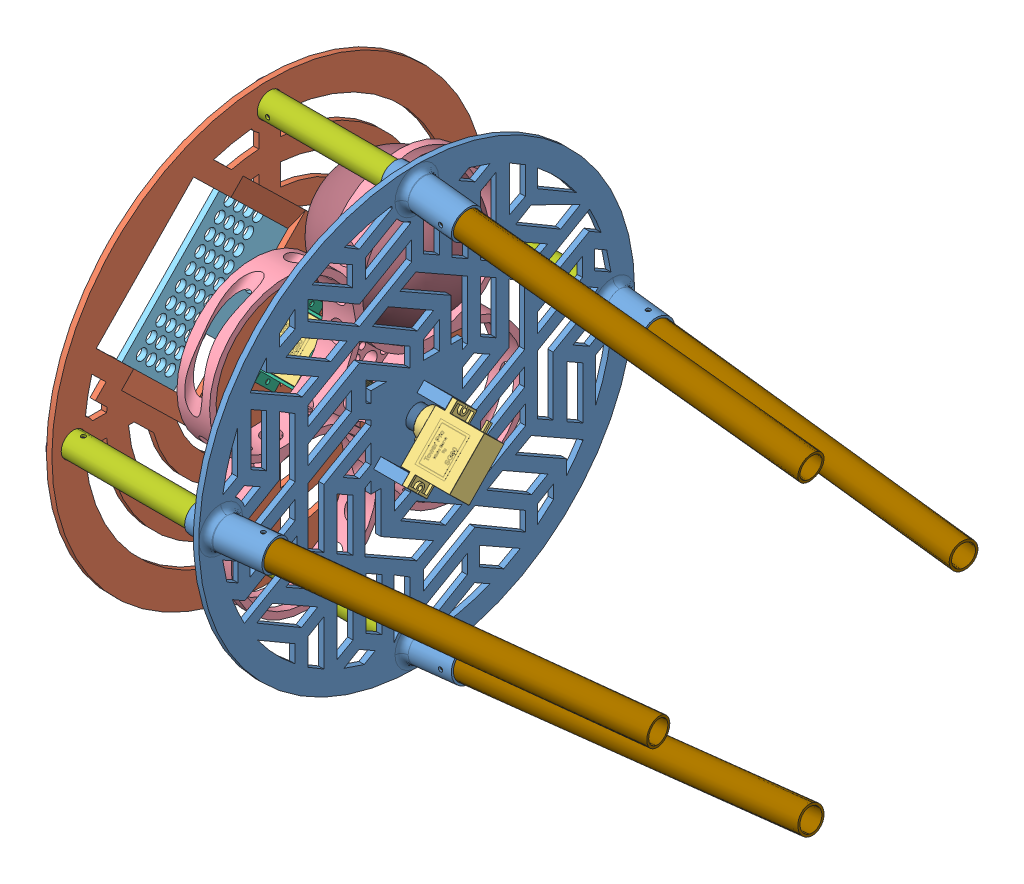
SolidWorks assembly Yük Bırakma Mekanizması Vol.4, configuration Varsayılan. Lengths in mm.
Overall size (264.31 282.82 282.82).
33 component instances, 22 part files, 41 mates.
Components (placement in the parent):
- Üst Tabla-1: Üst Tabla [Varsayılan] at (22.8768 -212.3675 0.7658) x (0 1 0) z (0 0 1) size (200 33.66 200)
- Alt Tabla-1: Alt Tabla [Varsayılan] at (-47.1232 -212.3675 0.7658) x (0 -0.716174 0.697921) z (0 0.697921 0.716174) size (200 15.35 200)
- TP SG90-1: TP SG90 [Varsayılan] at (-20.5232 -212.3747 0.7727) x (0 -0.697921 -0.716174) z (0 0.716174 -0.697921) size (12.64 29.82 33.01)
- Yük Tutucu-1: Yük Tutucu [Varsayılan] at (1.2768 -212.3675 0.7658) x (0 -0.596582 -0.802552) z (0 0.802552 -0.596582) size (166 20 166)
- TP SG90-2: TP SG90 [Varsayılan] at (54.1268 -216.1275 4.4299) x (0 -0.697921 -0.716174) z (0 0.716174 -0.697921) size (12.64 29.82 33.01)
- Alt Kapak-1: Alt Kapak [Varsayılan] at (-49.6232 -142.9176 16.8643) x (0 -0.716174 0.697921) z (0 0.697921 0.716174) size (73 2.5 85)
- Denge Parçası-1: Denge Parçası [Varsayılan] at (-36.3732 -208.3933 -11.8341) x (0 -0.716174 0.697921) z (0 0.697921 0.716174) size (33.3 22.15 19.25)
- karbonfiber boru 11x70-5: karbonfiber boru 11x70 [Varsayılan] at (-47.1232 -302.3675 0.7658) x (0 1 0) z (1 0 0) size (11 11 67.5)
- Bağlantı Parçası-1: Bağlantı Parçası [Varsayılan] at (-49.1232 -302.3675 0.7658) x (0 1 0) z (0 0 -1) size (16.34 15 16.34)
- karbonfiber boru 11x70-12: karbonfiber boru 11x70 [Varsayılan] at (-47.1232 -212.3675 90.7658) x (0 0 -1) z (1 0 0) size (11 11 67.5)
- karbonfiber boru 11x70-13: karbonfiber boru 11x70 [Varsayılan] at (-47.1232 -122.3675 0.7658) x (0 -1 0) z (1 0 0) size (11 11 67.5)
- karbonfiber boru 11x70-14: karbonfiber boru 11x70 [Varsayılan] at (-47.1232 -212.3675 -89.2342) x (0 0 1) z (1 0 0) size (11 11 67.5)
- Bağlantı Parçası-5: Bağlantı Parçası [Varsayılan] at (-49.1232 -212.3675 90.7658) x (0 0 -1) z (0 -1 0) size (16.34 15 16.34)
- Bağlantı Parçası-6: Bağlantı Parçası [Varsayılan] at (-49.1232 -122.3675 0.7658) x (0 -1 0) z (0 0 1) size (16.34 15 16.34)
- Bağlantı Parçası-7: Bağlantı Parçası [Varsayılan] at (-49.1232 -212.3675 -89.2342) x (0 0 1) z (0 1 0) size (16.34 15 16.34)
- karbonfiber boru 12x169-2: karbonfiber boru 12x169 [Varsayılan] at (35.8145 -212.3675 89.6511) x (0 1 0) z (0.993768 0 -0.111469) size (12 12 169)
- karbonfiber boru 12x169-9: karbonfiber boru 12x169 [Varsayılan] at (35.8145 -301.2529 0.7658) x (0 0 1) z (0.993768 0.111469 0) size (12 12 169)
- karbonfiber boru 12x169-10: karbonfiber boru 12x169 [Varsayılan] at (35.8145 -212.3675 -88.1195) x (0 -1 0) z (0.993768 0 0.111469) size (12 12 169)
- karbonfiber boru 12x169-11: karbonfiber boru 12x169 [Varsayılan] at (35.8145 -123.4822 0.7658) x (0 0 -1) z (0.993768 -0.111469 0) size (12 12 169)
- Aktarma Parçası-2: Aktarma Parçası [Varsayılan] at (27.3268 -212.3675 0.7658) x (0 0.18119 0.983448) z (0 -0.983448 0.18119) size (9.65 15 9.65)
- alt kapak bağlantısı-1: alt kapak bağlantısı [Varsayılan] at (-46.6232 -208.6148 -2.8913) x (0 -0.717149 0.69692) z (0 -0.69692 -0.717149) size (5.8 3 10.81)
- Yivli mil-1: Yivli mil [Varsayılan] at (-11.7232 -212.3675 0.7658) x (0 0.999999 0.001718) z (0 0.001718 -0.999999) size (5.06 32.34 5.78)
- Top-1: Top [Varsayılan] at (-14.6232 -173.845 -27.8701) x (-0.869488 -0.236482 -0.433667) z (-0.460523 0.070599 0.884836) size (60 60 60)
- inafag_625-2z_6leky27aadc6c6egwocnas8n-1: inafag_625-2z_6leky27aadc6c6egwocnas8n [Default] at (-14.2232 -212.3675 0.7658) x (-1 0 0) z (0 -0.938946 -0.344066) size (5.01 16 16)
  - inafag_625-2z_6leky27aadc6c6egwocnas8n_01-1: inafag_625-2z_6leky27aadc6c6egwocnas8n_01 [Default] at origin size (5 16 16)
  - inafag_625-2z_6leky27aadc6c6egwocnas8n_02-1: inafag_625-2z_6leky27aadc6c6egwocnas8n_02 [Default] at origin size (5.01 8.5 8.5)
  - inafag_625-2z_6leky27aadc6c6egwocnas8n_03-1: inafag_625-2z_6leky27aadc6c6egwocnas8n_03 [Default] at origin size (3.8 11.99 11.99)
  - inafag_625-2z_6leky27aadc6c6egwocnas8n_04-1: inafag_625-2z_6leky27aadc6c6egwocnas8n_04 [Default] at origin size (4.05 4.13 4.2)
  - inafag_625-2z_6leky27aadc6c6egwocnas8n_05-1: inafag_625-2z_6leky27aadc6c6egwocnas8n_05 [Default] at origin size (3.85 4.1 3.78)
  - inafag_625-2z_6leky27aadc6c6egwocnas8n_06-1: inafag_625-2z_6leky27aadc6c6egwocnas8n_06 [Default] at origin size (3.6 4.12 3.67)
  - inafag_625-2z_6leky27aadc6c6egwocnas8n_07-1: inafag_625-2z_6leky27aadc6c6egwocnas8n_07 [Default] at origin size (4.06 4.14 4.12)
  - inafag_625-2z_6leky27aadc6c6egwocnas8n_08-1: inafag_625-2z_6leky27aadc6c6egwocnas8n_08 [Default] at origin size (0.3 13.2 13.2)
  - inafag_625-2z_6leky27aadc6c6egwocnas8n_09-1: inafag_625-2z_6leky27aadc6c6egwocnas8n_09 [Default] at origin size (0.3 13.2 13.2)
Mates (geometry in assembly coordinates):
- Eş Merkezli1: concentric anti-aligned: cylinder of Üst Tabla-1 through (20.3768 -212.3675 0.7658) axis (1 0 0) radius 100; cylinder of Alt Tabla-1 through (-44.6232 -212.3675 0.7658) axis (-1 0 0) radius 100
- Eş Merkezli2: concentric aligned: cylinder of TP SG90-1 through (-43.0232 -213.0909 1.4707) axis (-1 0 0) radius 1.375; cylinder of Alt Tabla-1 through (-44.6232 -213.0909 1.4707) axis (-1 0 0) radius 1.775
- Çakışık3: coincident aligned: plane of Alt Tabla-1 through (-47.1232 -212.3675 0.7658) normal (-1 0 0); plane of TP SG90-1 through (-47.1232 -209.1072 -2.4115) normal (-1 0 0)
- Paralel1: parallel aligned: plane of Alt Tabla-1 through (-44.6232 -178.2832 -10.1089) normal (0 0.697921 0.716174); plane of TP SG90-1 through (-31.7732 -208.0127 5.2488) normal (0 0.697921 0.716174)
- Paralel2: parallel aligned: plane of Alt Tabla-1 through (-44.6232 -178.2832 -10.1089) normal (0 0.697921 0.716174); plane of TP SG90-2 through (42.8768 -211.7654 8.9059) normal (0 0.697921 0.716174)
- Çakışık8: coincident anti-aligned: plane of Alt Tabla-1 through (-47.1232 -212.3675 0.7658) normal (-1 0 0); plane of Alt Kapak-1 through (-47.1232 -142.9176 16.8643) normal (1 0 0)
- Eş Merkezli10: concentric aligned: cylinder of Alt Tabla-1 through (-44.6232 -208.6148 -2.8913) axis (-1 0 0) radius 6.65; cylinder of Alt Kapak-1 through (-47.1232 -208.6148 -2.8913) axis (-1 0 0) radius 3
- Açıyı Sınırla2: limit planar angle = 0 rad anti-aligned: plane of Alt Kapak-1 through (-47.1232 -195.1983 67.8126) normal (0 -0.716174 0.697921); plane of Alt Tabla-1 through (-51.1232 -237.4336 25.193) normal (0 0.716174 -0.697921)
- Uzaklık1: distance = 0.15 mm anti-aligned: plane of TP SG90-1 through (-36.3732 -204.1387 -7.2533) normal (0 0.716174 -0.697921); plane of Denge Parçası-1 through (-36.3732 -199.6693 -2.8819) normal (0 -0.716174 0.697921)
- Çakışık10: coincident anti-aligned: plane of TP SG90-1 through (-36.3732 -200.5578 -10.743) normal (1 0 0); plane of Denge Parçası-1 through (-36.3732 -199.6693 -2.8819) normal (-1 0 0)
- Çakışık12: coincident aligned: plane of TP SG90-1 through (-31.7732 -208.0127 5.2488) normal (0 0.697921 0.716174); plane of Denge Parçası-1 through (-36.3732 -199.6693 -2.8819) normal (0 0.697921 0.716174)
- Çakışık19: coincident aligned: plane of Alt Tabla-1 through (-47.1232 -212.3675 0.7658) normal (-1 0 0); plane of karbonfiber boru 11x70-5 through (-47.1232 -302.3675 0.7658) normal (-1 0 0)
- Çakışık20: coincident anti-aligned: plane of Üst Tabla-1 through (20.3768 -212.3675 0.7658) normal (-1 0 0); plane of karbonfiber boru 11x70-5 through (20.3768 -302.3675 0.7658) normal (1 0 0)
- Eş Merkezli15: concentric aligned: cylinder of Alt Tabla-1 through (-38.7732 -302.3675 0.7658) axis (-1 0 0) radius 5.7; cylinder of karbonfiber boru 11x70-5 through (20.3768 -302.3675 0.7658) axis (-1 0 0) radius 5.5
- Eş Merkezli17: concentric anti-aligned: cylinder of Üst Tabla-1 through (12.8768 -302.3675 0.7658) axis (1 0 0) radius 5.55; cylinder of karbonfiber boru 11x70-5 through (20.3768 -302.3675 0.7658) axis (-1 0 0) radius 5.5
- Eş Merkezli19: concentric anti-aligned: cylinder of Üst Tabla-1 through (20.3768 -212.3675 0.7658) axis (1 0 0) radius 100; cylinder of Yük Tutucu-1 through (-18.7232 -212.3675 0.7658) axis (-1 0 0) radius 2.4
- Eş Merkezli21: concentric anti-aligned: cylinder of Üst Tabla-1 through (20.3768 -212.3675 0.7658) axis (1 0 0) radius 100; cylinder of TP SG90-2 through (31.6268 -212.3675 0.7658) axis (-1 0 0) radius 6.25
- Paralel10: parallel aligned: plane of Üst Tabla-1 through (35.8768 -208.6708 -11.7033) normal (0 -0.697921 -0.716174); plane of TP SG90-2 through (42.8768 -220.4895 -0.0462) normal (0 -0.697921 -0.716174)
- Paralel11: parallel aligned: plane of Üst Tabla-1 through (35.8768 -199.8072 -2.6079) normal (0 0.716174 -0.697921); plane of TP SG90-2 through (35.8768 -204.3106 -7.0858) normal (0 0.716174 -0.697921)
- Eş Merkezli22: concentric aligned: cylinder of karbonfiber boru 11x70-5 through (20.3768 -302.3675 0.7658) axis (-1 0 0) radius 4.5; cylinder of Bağlantı Parçası-1 through (-34.1232 -302.3675 0.7658) axis (-1 0 0) radius 4.4
- Çakışık30: coincident anti-aligned: plane of Alt Tabla-1 through (-47.1232 -212.3675 0.7658) normal (-1 0 0); plane of Bağlantı Parçası-1 through (-47.1232 -302.3675 0.7658) normal (1 0 0)
- Eş Merkezli23: concentric anti-aligned: cylinder of karbonfiber boru 11x70-5 through (-40.1232 -302.3675 -4.7342) axis (0 0 1) radius 1; cylinder of Bağlantı Parçası-1 through (-40.1232 -302.3675 8.9371) axis (0 0 -1) radius 1
- Eş Merkezli24: concentric anti-aligned: cylinder of Üst Tabla-1 through (35.8145 -212.3675 89.6511) axis (0.993768 0 -0.111469) radius 6.05; cylinder of karbonfiber boru 12x169-2 through (203.7612 -212.3675 70.8128) axis (-0.993768 0 0.111469) radius 6
- Çakışık31: coincident anti-aligned: plane of Üst Tabla-1 through (35.8145 -212.3675 89.6511) normal (0.993768 0 -0.111469); plane of karbonfiber boru 12x169-2 through (35.8145 -212.3675 89.6511) normal (-0.993768 0 0.111469)
- Eş Merkezli27: concentric aligned: cylinder of Üst Tabla-1 through (15.3768 -122.3675 100.7658) axis (0 0 -1) radius 1; cylinder of karbonfiber boru 11x70-13 through (15.3768 -122.3675 6.2658) axis (0 0 -1) radius 1
- Eş Merkezli28: concentric aligned: cylinder of Üst Tabla-1 through (40.7833 -312.3675 89.0937) axis (0 1 0) radius 1; cylinder of karbonfiber boru 12x169-2 through (40.7833 -218.3675 89.0937) axis (0 1 0) radius 1
- Coincident4: coincident anti-aligned: plane of Üst Tabla-1 through (35.8768 -212.3675 0.7658) normal (1 0 0); plane of TP SG90-2 through (35.8768 -207.8915 -3.5962) normal (-1 0 0)
- Coincident5: coincident anti-aligned: plane of TP SG90-2 through (24.3268 -212.3675 0.7658) normal (-1 0 0); plane of Aktarma Parçası-2 through (24.3268 -212.3675 0.7658) normal (1 0 0)
- Concentric2: concentric aligned: cylinder of Üst Tabla-1 through (20.3768 -212.3675 0.7658) axis (1 0 0) radius 5; cylinder of Aktarma Parçası-2 through (12.3268 -212.3675 0.7658) axis (1 0 0) radius 4.825
- Eş Merkezli29: concentric anti-aligned: cylinder of Alt Kapak-1 through (-47.1232 -208.6148 -2.8913) axis (-1 0 0) radius 3; cylinder of alt kapak bağlantısı-1 through (-49.6232 -208.6148 -2.8913) axis (1 0 0) radius 2.9
- Çakışık32: coincident aligned: plane of Alt Kapak-1 through (-49.6232 -142.9176 16.8643) normal (-1 0 0); plane of alt kapak bağlantısı-1 through (-49.6232 -208.6148 -2.8913) normal (-1 0 0)
- Paralel12: parallel anti-aligned: plane of Alt Kapak-1 through (-47.1232 -178.4723 39.5344) normal (0 -0.843185 0.537624); plane of alt kapak bağlantısı-1 through (-49.6232 -206.5083 -4.2345) normal (0 0.843185 -0.537624)
- Eş Merkezli30: concentric aligned: cylinder of Yük Tutucu-1 through (-2.7232 -212.3675 0.7658) axis (-1 0 0) radius 2.5; cone of Yivli mil-1 through (-11.2232 -212.3675 0.7658) axis (-1 0 0)
- Çakışık34: coincident anti-aligned: plane of Yük Tutucu-1 through (-11.7232 -212.3675 0.7658) normal (1 0 0); plane of Yivli mil-1 through (-11.7232 -212.3675 0.7658) normal (-1 0 0)
- Paralel13: parallel anti-aligned: plane of Aktarma Parçası-2 through (17.3268 -212.3675 0.7658) normal (-1 0 0); plane of Yivli mil-1 through (20.3268 -212.3675 0.7658) normal (1 0 0)
- Eş Merkezli31: concentric anti-aligned: cylinder of Aktarma Parçası-2 through (17.3268 -212.3675 0.7658) axis (-1 0 0) radius 2.5; cone of Yivli mil-1 through (20.3268 -212.3675 0.7658) axis (1 0 0)
- Eş Merkezli32: concentric: cylinder of Yük Tutucu-1 through (-13.7232 -173.845 -27.8701) axis (1 0 0) radius 32; sphere of Top-1
- Teğet2: tangent anti-aligned: plane of Alt Tabla-1 through (-44.6232 -212.3675 0.7658) normal (1 0 0); sphere of Top-1
- Çakışık35: coincident: plane of Denge Parçası-1 through (-19.2232 -199.6693 -2.8819) normal (1 0 0); plane of ? through (-19.2232 -219.081 -1.6943) normal (-1 0 0)
- Çakışık36: coincident anti-aligned: plane of Yük Tutucu-1 through (-14.2232 -212.3675 0.7658) normal (-1 0 0); plane of inafag_625-2z_6leky27aadc6c6egwocnas8n-1/inafag_625-2z_6leky27aadc6c6egwocnas8n_02-1 through (-14.2232 -215.6773 -0.4471) normal (1 0 0)
- Eş Merkezli34: concentric anti-aligned: cylinder of Denge Parçası-1 through (-14.2232 -212.3675 0.7658) axis (-1 0 0) radius 8.125; cylinder of inafag_625-2z_6leky27aadc6c6egwocnas8n-1/inafag_625-2z_6leky27aadc6c6egwocnas8n_01-1 through (-16.7232 -212.3675 0.7658) axis (1 0 0) radius 8
